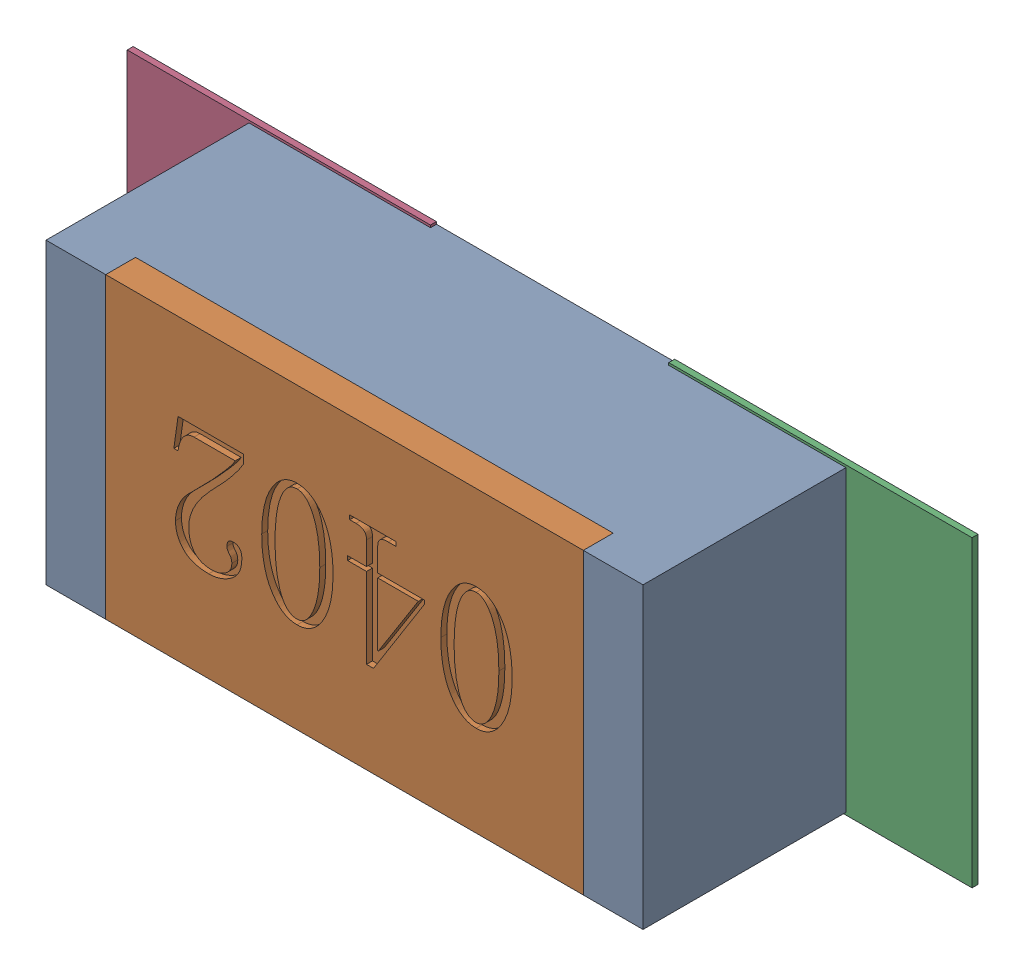
SolidWorks assembly R144, configuration Défaut. Lengths in mm.
Overall size (1.42 0.51 0.35).
5 component instances, 2 part files, 0 mates.
Components (placement in the parent):
- R0402-1: R0402 [Défaut] at (13.6652 -23.0377 0) x (-1 0 0) z (0 0 1) size (1 0.5 0.35)
- 6504207776-1: 6504207776 [Défaut] at (14.1223 -23.0378 0) size (0.51 0.51 0.01)
  - Extruded-1: Extruded [Défaut] at origin size (0.51 0.51 0.01)
- 6504207776-2: 6504207776 [Défaut] at (13.2152 -23.0378 0) size (0.51 0.51 0.01)
  - Extruded-1: Extruded [Défaut] at origin size (0.51 0.51 0.01)
